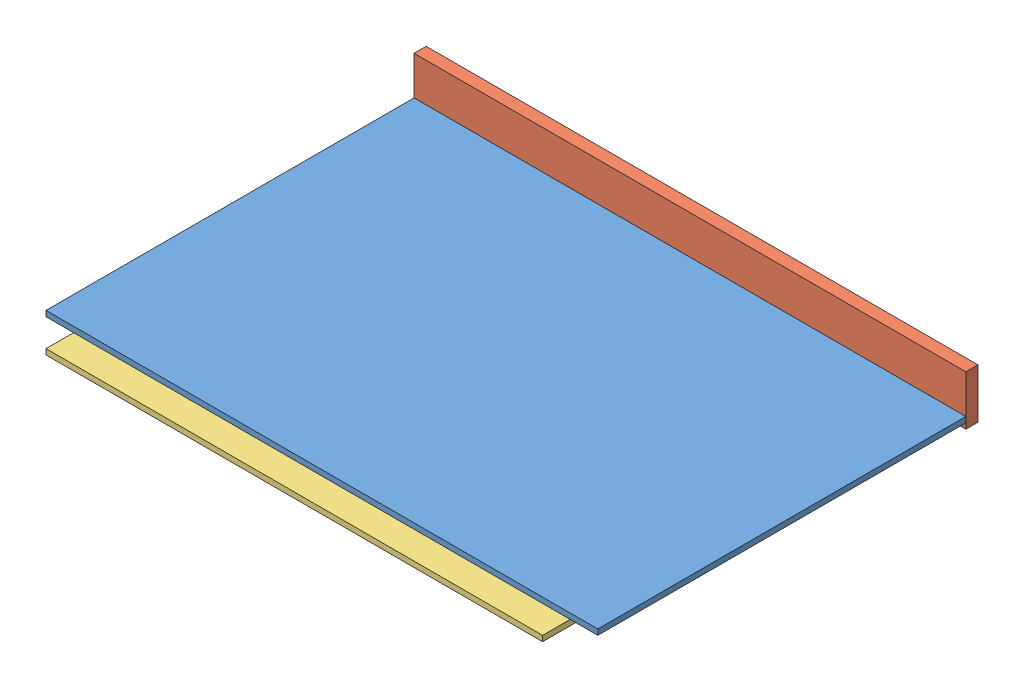
SolidWorks assembly Terrain_9_Partie_2, configuration Default. Lengths in mm.
Overall size (1000 90 739).
5 component instances, 4 part files, 12 mates.
Components (placement in the parent):
- planche_1000x667x10-1: planche_1000x667x10 [Default] at (-508.5557 82.8779 278.3118) size (1000 10 667)
- planche_1000x90x22-1: planche_1000x90x22 [Default] at (-508.5557 72.8779 -410.6882) size (1000 90 22)
- planche_900x100x10-1: planche_900x100x10 [Default] at (-458.5557 72.8779 328.3118) size (900 10 100)
- planche_900x100x10-2: planche_900x100x10 [Default] at (-458.5557 72.8779 -288.6882) size (900 10 100)
- planche_517x100x10-1: planche_517x100x10 [Default] at (-58.5557 72.8779 -288.6882) x (0 0 1) z (-1 0 0) size (517 10 100)
Mates (geometry in assembly coordinates):
- Coïncidente1: coincident anti-aligned: plane of planche_1000x667x10-1 through (-508.5557 92.8779 -388.6882) normal (0 0 -1); plane of ? through (-508.5557 121.2936 -388.6882) normal (0 0 1)
- Coïncidente2: coincident aligned: plane of planche_1000x667x10-1 through (491.4443 92.8779 278.3118) normal (1 0 0); plane of ? through (491.4443 31.2936 -388.6882) normal (1 0 0)
- Coïncidente3: coincident anti-aligned: plane of planche_1000x667x10-1 through (-508.5557 82.8779 -388.6882) normal (0 -1 0); plane of planche_900x100x10-1 through (-458.5557 82.8779 228.3118) normal (0 1 0)
- Coïncidente4: coincident anti-aligned: plane of planche_1000x667x10-1 through (-508.5557 82.8779 -388.6882) normal (0 -1 0); plane of planche_900x100x10-2 through (-458.5557 82.8779 -388.6882) normal (0 1 0)
- Coïncidente5: coincident anti-aligned: plane of ? through (-508.5557 121.2936 -388.6882) normal (0 0 1); plane of planche_900x100x10-2 through (-458.5557 82.8779 -388.6882) normal (0 0 -1)
- Coïncidente6: coincident aligned: plane of planche_900x100x10-1 through (441.4443 82.8779 328.3118) normal (1 0 0); plane of planche_900x100x10-2 through (441.4443 82.8779 -288.6882) normal (1 0 0)
- Distance1: distance = 50 mm aligned: plane of planche_900x100x10-1 through (-458.5557 82.8779 328.3118) normal (0 0 1); plane of planche_1000x667x10-1 through (-508.5557 92.8779 278.3118) normal (0 0 1)
- Distance2: distance = 50 mm aligned: plane of planche_1000x667x10-1 through (491.4443 92.8779 278.3118) normal (1 0 0); plane of planche_900x100x10-2 through (441.4443 82.8779 -288.6882) normal (1 0 0)
- Coïncidente9: coincident anti-aligned: plane of planche_1000x667x10-1 through (-508.5557 82.8779 -388.6882) normal (0 -1 0); plane of planche_517x100x10-1 through (41.4443 82.8779 -288.6882) normal (0 1 0)
- Coïncidente10: coincident anti-aligned: plane of planche_900x100x10-1 through (-458.5557 82.8779 228.3118) normal (0 0 -1); plane of planche_517x100x10-1 through (-58.5557 82.8779 228.3118) normal (0 0 1)
- Distance3: distance = 450 mm aligned: plane of planche_517x100x10-1 through (-58.5557 82.8779 -288.6882) normal (-1 0 0); plane of planche_1000x667x10-1 through (-508.5557 92.8779 278.3118) normal (-1 0 0)
- Coïncidente12: coincident aligned: plane of ? through (-508.5557 31.2936 -388.6882) normal (0 -1 0); plane of planche_900x100x10-2 through (-458.5557 72.8779 -388.6882) normal (0 -1 0)
